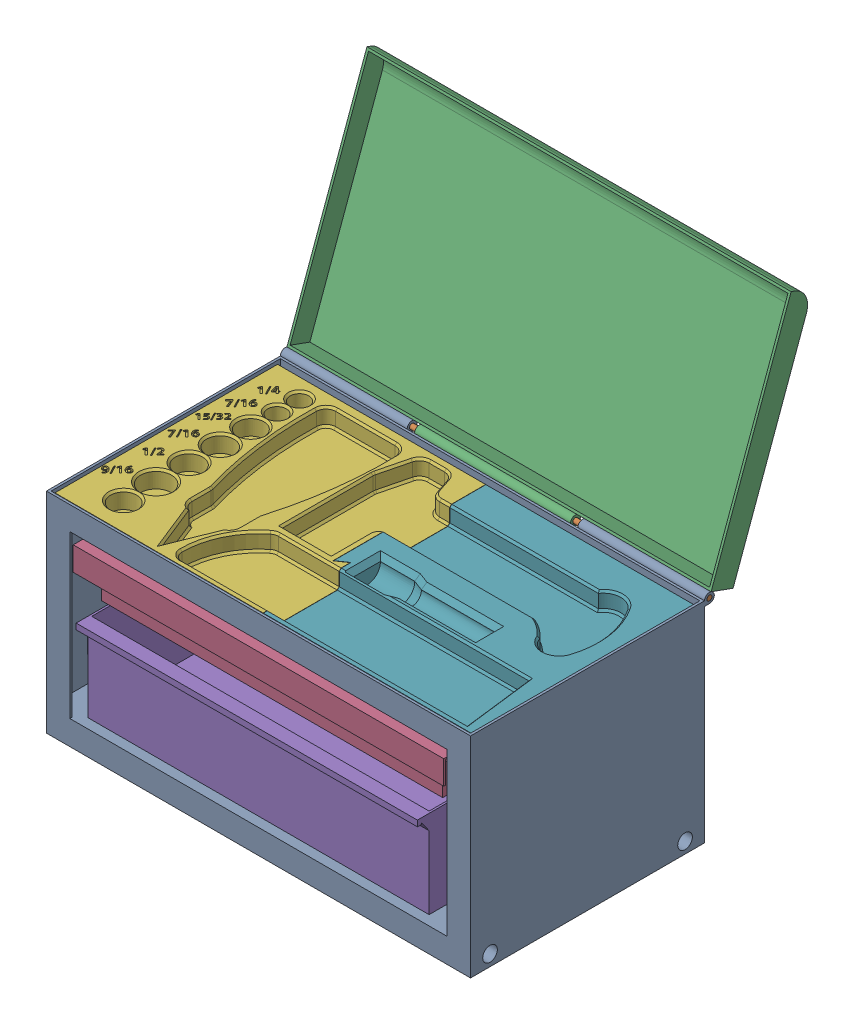
SolidWorks assembly SP-A0101-AC-Tool Box, configuration Default. Lengths in mm.
Overall size (276.23 283.8 230.73).
6 component instances, 6 part files, 19 mates.
Components (placement in the parent):
- SP-00001-AC-Box-1: SP-00001-AC-Box [Default] at (1.524 136.525 150.876) size (276.23 139.7 158.75)
- SP-00005-AA-Hinge Pin-2: SP-00005-AA-Hinge Pin [Default] at (276.225 136.525 -3.175) x (-1 0 0) z (0 0.655217 -0.75544) size (276.23 3.3 3.3)
- SP-00002-AA-Lid-3: SP-00002-AA-Lid [Default] at (1.524 281.2856 -55.8635) x (1 0 0) z (0 0.939693 -0.34202) size (276.23 18.41 158.75)
- SP-00003-AA-Upper Drawer-2: SP-00003-AA-Upper Drawer [Default] at (138.1125 83.7565 143.51) size (241.3 31.18 135.89)
- SP-00004-AA-lower drawer-2: SP-00004-AA-lower drawer [Default] at (138.1125 22.225 88.9) size (222.25 57.15 134.62)
- SP-00010-AD-Top Insert-1: SP-00010-AD-Top Insert [Default] at (1.524 122.809 150.876) size (273.6 12.7 147.51)
Mates (geometry in assembly coordinates):
- Concentric3: concentric aligned: cylinder of SP-00001-AC-Box-1 through (193.675 136.525 -3.175) axis (1 0 0) radius 1.651; cylinder of SP-00005-AA-Hinge Pin-2 through (0 136.525 -3.175) axis (1 0 0) radius 1.651
- Concentric4: concentric anti-aligned: cylinder of SP-00001-AC-Box-1 through (82.55 136.525 -3.175) axis (-1 0 0) radius 1.651; cylinder of SP-00005-AA-Hinge Pin-2 through (0 136.525 -3.175) axis (1 0 0) radius 1.651
- Coincident8: coincident aligned: plane of SP-00001-AC-Box-1 through (276.225 0 152.4) normal (1 0 0); plane of SP-00005-AA-Hinge Pin-2 through (276.225 136.525 -3.175) normal (1 0 0)
- Coincident10: coincident aligned: plane of SP-00001-AC-Box-1 through (276.225 0 152.4) normal (1 0 0); plane of SP-00002-AA-Lid-3 through (276.225 276.0732 -70.1845) normal (1 0 0)
- Concentric6: concentric anti-aligned: cylinder of SP-00005-AA-Hinge Pin-2 through (0 136.525 -3.175) axis (1 0 0) radius 1.651; cylinder of SP-00002-AA-Lid-3 through (188.9125 136.525 -3.175) axis (-1 0 0) radius 1.651
- Coincident13: coincident anti-aligned: plane of SP-00001-AC-Box-1 through (249.2375 102.235 184.2008) normal (-1 0 0); plane of SP-00003-AA-Upper Drawer-2 through (249.2375 86.2965 143.51) normal (1 0 0)
- Distance5: distance = 6.35 mm anti-aligned: plane of SP-00001-AC-Box-1 through (1.524 121.285 150.876) normal (0 -1 0); plane of SP-00003-AA-Upper Drawer-2 through (17.4625 114.935 143.51) normal (0 1 0)
- LimitDistance3: limit distance = 0 mm aligned: plane of SP-00003-AA-Upper Drawer-2 through (17.4625 114.935 152.4) normal (0 0 1); plane of SP-00001-AC-Box-1 through (0 0 152.4) normal (0 0 1)
- Coincident14: coincident anti-aligned: plane of SP-00001-AC-Box-1 through (249.2375 51.435 184.2008) normal (-1 0 0); plane of SP-00004-AA-lower drawer-2 through (249.2375 79.375 152.4) normal (1 0 0)
- Distance6: distance = 6.35 mm anti-aligned: plane of SP-00001-AC-Box-1 through (1.524 15.875 150.876) normal (0 1 0); plane of SP-00004-AA-lower drawer-2 through (138.1125 22.225 88.9) normal (0 -1 0)
- LimitDistance4: limit distance = 0 mm aligned: plane of SP-00001-AC-Box-1 through (0 0 152.4) normal (0 0 1); plane of SP-00004-AA-lower drawer-2 through (249.2375 79.375 152.4) normal (0 0 1)
- Coincident15: coincident: point of SP-00001-AC-Box-1
- Parallel1: parallel aligned: plane of SP-00001-AC-Box-1 through (1.524 136.525 150.876) normal (0 1 0)
- Parallel2: parallel aligned: plane of SP-00001-AC-Box-1 through (1.524 136.525 150.876) normal (1 0 0)
- Parallel3: parallel aligned: plane of SP-00001-AC-Box-1 through (1.524 136.525 150.876) normal (0 0 1)
- LimitAngle1: limit planar angle = 1.919862 rad anti-aligned: plane of SP-00002-AA-Lid-3 through (1.524 281.2856 -55.8635) normal (0 0.34202 0.939693); plane of SP-00001-AC-Box-1 through (1.524 136.525 150.876) normal (0 1 0)
- Coincident17: coincident anti-aligned: plane of SP-00001-AC-Box-1 through (1.524 -312.0725 150.876) normal (1 0 0); plane of SP-00010-AD-Top Insert-1 through (1.524 124.333 150.876) normal (-1 0 0)
- Coincident18: coincident anti-aligned: plane of SP-00001-AC-Box-1 through (1.524 122.809 150.876) normal (0 1 0); plane of SP-00010-AD-Top Insert-1 through (1.524 122.809 150.876) normal (0 -1 0)
- Coincident19: coincident anti-aligned: plane of SP-00001-AC-Box-1 through (1.524 -312.0725 150.876) normal (0 0 -1); plane of SP-00010-AD-Top Insert-1 through (1.524 124.333 150.876) normal (0 0 1)
